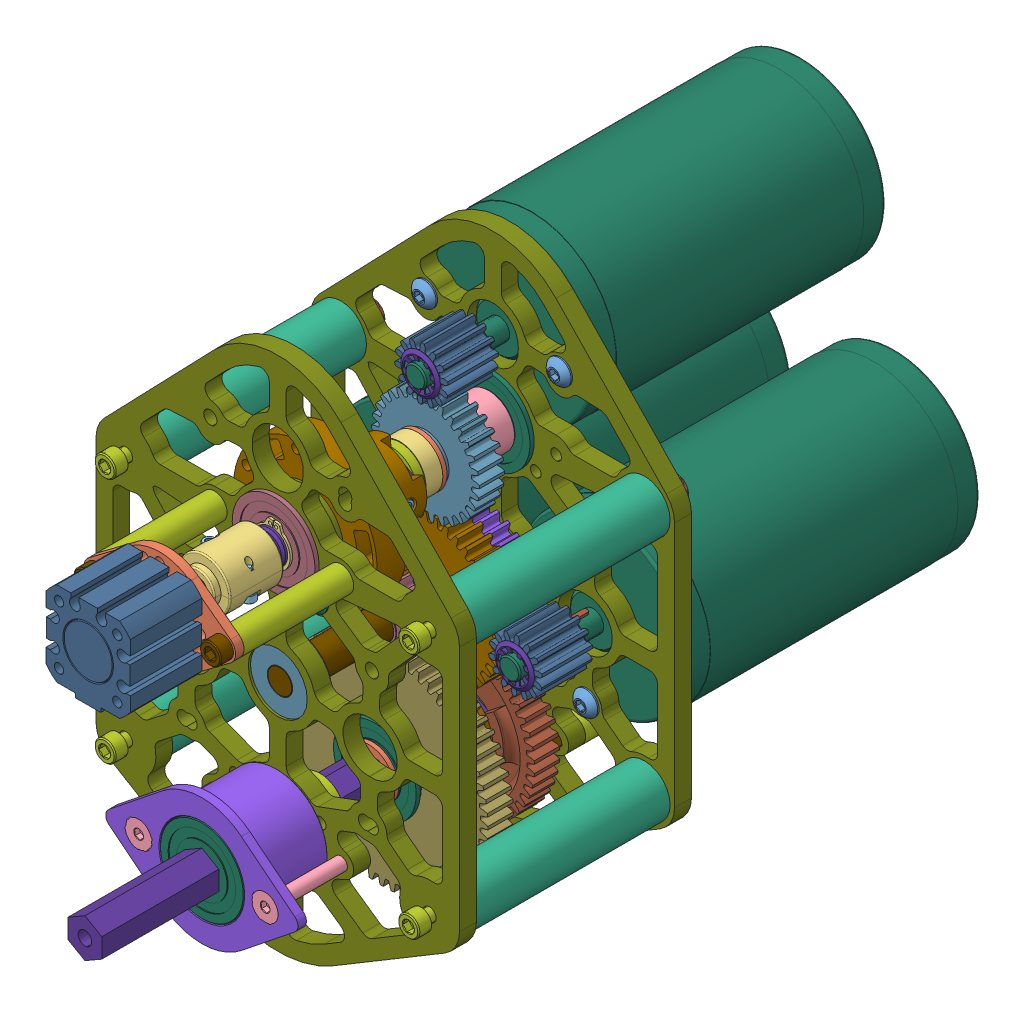
SolidWorks assembly 217-3433-PTO CONFIG STEP, configuration Default. Lengths in mm.
Overall size (140.54 205.19 274.51).
115 component instances, 47 part files, 0 mates.
Components (placement in the parent):
- 217-2428-027 Rev1_97414A630-1: 217-2428-027 Rev1_97414A630 [Default] at (0 -47.0408 -31.6122) x (0 0 1) z (-1 0 0) size (0.64 5.89 7.9)
- 217-3423-005 Rev1-1: 217-3423-005 Rev1 [Default] at (0 -47.0408 -46.0375) size (57.15 38.1 3.17)
- 217-3195-200 Rev1-1: 217-3195-200 Rev1 [Default] at (0 -47.0408 -35.3587) x (-1 0 0) z (0 0 -1) size (20.44 19.56 22.68)
  - 217-3195-010 Rev1-1: 217-3195-010 Rev1 [Default] x (-1 0 0) z (0 0 1) size (19.61 11.78 22.68)
  - 217-3195-010 Rev1-2: 217-3195-010 Rev1 [Default] at origin size (19.61 11.78 22.68)
  - 217-2778-NCQ8A075-050M_1032_Nut_90545A111-1: 217-2778-NCQ8A075-050M_1032_Nut_90545A111 [Default] at (0 0 2.5527) x (-0.5 0.866025 0) z (0 0 1) size (9.53 11 3.39)
  - 91251A107_91251A107-1: 91251A107_91251A107 [Default] at (-7.4168 -4.9375 -0.635) x (1 0 0) z (0 -1 0) size (4.65 4.65 10.79)
  - 91251A107_91251A107-2: 91251A107_91251A107 [Default] at (7.4168 4.9375 -0.635) x (-0.837169 0 -0.546944) z (0 1 0) size (4.65 4.65 10.79)
- 217-3489-1: 217-3489 [Default] at (0 -47.0408 -28.9135) x (0 0 -1) z (0.779786 -0.626046 0) size (4.77 12.7 12.7)
- 217-2428-027 Rev1_97414A630-2: 217-2428-027 Rev1_97414A630 [Default] at (0 45.7708 99.4031) x (0 0 1) z (-0.998671 -0.051538 0) size (0.64 5.89 7.9)
- 217-3195-200 Rev1-2: 217-3195-200 Rev1 [Default] at (0 45.7708 103.048) x (-1 0 0) z (0 0 1) size (20.44 19.56 22.68)
  - 217-3195-010 Rev1-1: 217-3195-010 Rev1 [Default] x (-1 0 0) z (0 0 1) size (19.61 11.78 22.68)
  - 217-3195-010 Rev1-2: 217-3195-010 Rev1 [Default] at origin size (19.61 11.78 22.68)
  - 217-2778-NCQ8A075-050M_1032_Nut_90545A111-1: 217-2778-NCQ8A075-050M_1032_Nut_90545A111 [Default] at (0 0 2.5527) x (-0.5 0.866025 0) z (0 0 1) size (9.53 11 3.39)
  - 91251A107_91251A107-1: 91251A107_91251A107 [Default] at (-7.4168 -4.9375 -0.635) x (1 0 0) z (0 -1 0) size (4.65 4.65 10.79)
  - 91251A107_91251A107-2: 91251A107_91251A107 [Default] at (7.4168 4.9375 -0.635) x (-0.837169 0 -0.546944) z (0 1 0) size (4.65 4.65 10.79)
- 217-3489-2: 217-3489 [Default] at (0 45.7708 96.6028) x (0 0 -1) z (-0.103791 0.994599 0) size (4.77 12.7 12.7)
- 217-3423-005 Rev1-2: 217-3423-005 Rev1 [Default] at (0 45.7708 127) size (57.15 38.1 3.17)
- 217-3423-006 Rev1-1: 217-3423-006 Rev1 [Default] at (-23.8125 -47.0408 -23.8125) x (0 0 1) z (-0.878816 -0.477161 0) size (41.27 9.53 9.53)
- 217-3423-006 Rev1-2: 217-3423-006 Rev1 [Default] at (23.8125 -47.0408 -23.8125) x (0 0 1) z (-1 0 0) size (41.27 9.53 9.53)
- 217-3423-008 Rev1-1: 217-3423-008 Rev1 [Default] at (0 -47.0408 -24.043) x (0 1 0) z (0 0 1) size (7.14 7.14 57.15)
- 217-3423-008 Rev1-2: 217-3423-008 Rev1 [Default] at (0 45.7708 91.7323) x (0 -1 0) z (0 0 -1) size (7.14 7.14 57.15)
- 217-3423-009 Rev1-1: 217-3423-009 Rev1 [Default] at (0 -47.0408 19.5624) x (-1 0 0) z (0 0 1) size (26.99 26.99 13.24)
- 217-3423-009 Rev1-2: 217-3423-009 Rev1 [Default] at (0 45.7708 48.1269) x (-1 0 0) z (0 0 1) size (26.99 26.99 13.24)
- 217-2778-001 Rev2_NCQ8A075-050M-1: 217-2778-001 Rev2_NCQ8A075-050M [Default] at (0 45.7708 142.0495) x (1 0 0) z (0 0 -1) size (31.75 33.34 53.29)
  - 217-2778-NCQ8A075-050M_NCQ8 Tube_075A-1: 217-2778-NCQ8A075-050M_NCQ8 Tube_075A [Default] at origin size (31.75 33.34 26.92)
  - 217-2778-NCQ8A075-050M_NCQ8 Rod_075M-1: 217-2778-NCQ8A075-050M_NCQ8 Rod_075M [Default] at (0 0 4.561) x (-1 0 0) z (0 0 1) size (18.95 18.95 35.27)
  - 217-2778-NCQ8A075-050M_Snap Ring_075-1: 217-2778-NCQ8A075-050M_Snap Ring_075 [Default] at (0 0 10.362) size (21 20.74 0.97)
- 217-2778-001 Rev2_NCQ8A075-050M-2: 217-2778-001 Rev2_NCQ8A075-050M [Default] at (0 -47.0408 -61.087) x (-1 0 0) z (0 0 1) size (31.75 33.34 53.29)
  - 217-2778-NCQ8A075-050M_NCQ8 Tube_075A-1: 217-2778-NCQ8A075-050M_NCQ8 Tube_075A [Default] at origin size (31.75 33.34 26.92)
  - 217-2778-NCQ8A075-050M_NCQ8 Rod_075M-1: 217-2778-NCQ8A075-050M_NCQ8 Rod_075M [Default] at (0 0 4.561) x (-1 0 0) z (0 0 1) size (18.95 18.95 35.27)
  - 217-2778-NCQ8A075-050M_Snap Ring_075-1: 217-2778-NCQ8A075-050M_Snap Ring_075 [Default] at (0 0 10.362) size (21 20.74 0.97)
- 217-2731-1: 217-2731 [Default] at (0 -47.0408 3.175) x (-0.539745 -0.841828 0) z (0.841828 -0.539745 0) size (31.12 7.94 31.12)
- 217-2731-2: 217-2731 [Default] at (0 45.7708 77.7875) x (0.750662 -0.660687 0) z (-0.660687 -0.750662 0) size (31.12 7.94 31.12)
- 217-2733-1: 217-2733 [Default] at (0 0 4.7625) x (0 0 -1) z (0.79471 -0.606989 0) size (7.11 24.61 24.61)
- 217-2733-2: 217-2733 [Default] at (0 0 76.2) x (0 0 1) z (-0.575096 -0.818086 0) size (7.11 24.61 24.61)
- 217-2734-1: 217-2734 [Default] at (0 -47.0408 104.775) x (0 -1 0) z (-1 0 0) size (31.12 7.94 31.12)
- 217-2734-2: 217-2734 [Default] at (0 45.7708 -3.175) x (-0.32713 0.944979 0) z (0.944979 0.32713 0) size (31.12 7.94 31.12)
- 217-2734-3: 217-2734 [Default] at (0 -47.0408 39.6557) x (-0.32713 0.944979 0) z (0.944979 0.32713 0) size (31.12 7.94 31.12)
- 217-2743-1: 217-2743 [Default] at (0 -47.0408 7.9057) x (0 0 -1) z (0.947967 0.31837 0) size (7.94 28.57 28.57)
- 217-2743-2: 217-2743 [Default] at (0 45.7708 73.025) x (0 0 -1) z (0.939414 -0.342784 0) size (7.94 28.57 28.57)
- 217-2614-002_98430A132-1: 217-2614-002_98430A132 [Default] at (35.4115 -3.81 31.1531) x (0 0 -1) z (-0.444133 -0.895961 0) size (1.2 14.83 14.83)
- 217-2614-002_98430A132-2: 217-2614-002_98430A132 [Default] at (35.4115 -3.81 9.9695) x (0 0 1) z (-0.864814 -0.502092 0) size (1.2 14.83 14.83)
- 217-2614-002_98430A132-3: 217-2614-002_98430A132 [Default] at (-35.4115 -3.81 31.1531) x (0 0 -1) z (-0.867628 -0.497214 0) size (1.2 14.83 14.83)
- 217-2614-002_98430A132-4: 217-2614-002_98430A132 [Default] at (-35.4115 -3.81 9.9695) x (0 0 1) z (-0.989494 0.144574 0) size (1.2 14.83 14.83)
- 217-2614-002_98430A132-5: 217-2614-002_98430A132 [Default] at (0 73.7616 31.1531) x (0 0 -1) z (0.241649 -0.970364 0) size (1.2 14.83 14.83)
- 217-2614-002_98430A132-6: 217-2614-002_98430A132 [Default] at (0 73.7616 9.9695) x (0 0 1) z (-0.864814 -0.502092 0) size (1.2 14.83 14.83)
- 217-3421-007 Rev1-1: 217-3421-007 Rev1 [Default] at (23.8125 45.7708 128.5875) x (0 0 -1) z (0.991978 -0.126413 0) size (55.85 7.92 7.92)
- 217-3421-007 Rev1-2: 217-3421-007 Rev1 [Default] at (-23.8125 45.7708 128.5875) x (0 0 -1) z (0.991978 -0.126413 0) size (55.85 7.92 7.92)
- 217-3421-007 Rev1-3: 217-3421-007 Rev1 [Default] at (23.8125 -47.0408 -47.625) x (0 0 1) z (-0.993182 -0.116573 0) size (55.85 7.92 7.92)
- 217-3421-007 Rev1-4: 217-3421-007 Rev1 [Default] at (-23.8125 -47.0408 -47.625) x (0 0 1) z (-0.993182 -0.116573 0) size (55.85 7.92 7.92)
- 217-3421-009 Rev1-1: 217-3421-009 Rev1 [Default] at (-25.4 73.7616 3.175) x (0 0 -1) z (0.999228 -0.039284 0) size (15.78 9.26 9.25)
- 217-3421-009 Rev1-2: 217-3421-009 Rev1 [Default] at (35.4115 21.59 3.175) x (0 0 -1) z (0.999228 -0.039284 0) size (15.78 9.26 9.25)
- 217-3421-009 Rev1-3: 217-3421-009 Rev1 [Default] at (25.4 73.7616 3.175) x (0 0 -1) z (0.656255 -0.754539 0) size (15.78 9.26 9.25)
- 217-3421-009 Rev1-4: 217-3421-009 Rev1 [Default] at (-35.4115 21.59 3.175) x (0 0 -1) z (0.999228 -0.039284 0) size (15.78 9.26 9.25)
- 217-3421-009 Rev1-5: 217-3421-009 Rev1 [Default] at (-35.4115 -29.21 3.175) x (0 0 -1) z (0.999228 -0.039284 0) size (15.78 9.26 9.25)
- 217-3421-009 Rev1-6: 217-3421-009 Rev1 [Default] at (35.4115 -29.21 3.175) x (0 0 -1) z (0.999228 -0.039284 0) size (15.78 9.26 9.25)
- 217-3421-010 Rev1-1: 217-3421-010 Rev1 [Default] at (57.15 45.7708 -3.175) x (0.017497 0.999847 0) z (-0.999847 0.017497 0) size (9.53 6.13 11)
- 217-3421-010 Rev1-2: 217-3421-010 Rev1 [Default] at (57.15 -47.0408 -3.175) x (0.017497 0.999847 0) z (-0.999847 0.017497 0) size (9.53 6.13 11)
- 217-3421-010 Rev1-3: 217-3421-010 Rev1 [Default] at (-57.15 45.7708 -3.175) x (0.017497 0.999847 0) z (-0.999847 0.017497 0) size (9.53 6.13 11)
- 217-3421-010 Rev1-4: 217-3421-010 Rev1 [Default] at (-57.15 -47.0408 -3.175) x (0.017497 0.999847 0) z (-0.999847 0.017497 0) size (9.53 6.13 11)
- 217-3421-011 Rev2_97633A200-1: 217-3421-011 Rev2_97633A200 [Default] at (0 45.7708 86.1695) x (0 0 1) z (-0.99554 0.094343 0) size (0.89 16.1 14.34)
- 217-3421-011 Rev2_97633A200-2: 217-3421-011 Rev2_97633A200 [Default] at (0 -47.0408 -5.2388) x (0 0 1) z (-0.999986 0.005305 0) size (0.89 16.1 14.34)
- 217-3422-007 Rev1-1: 217-3422-007 Rev1 [Default] at (23.8125 -47.0408 109.4868) x (0 0 1) z (-0.947089 0.320972 0) size (35.11 10.21 10.21)
- 217-3422-007 Rev1-2: 217-3422-007 Rev1 [Default] at (-23.8125 -47.0408 109.4868) x (0 0 1) z (-0.947089 0.320972 0) size (35.11 10.21 10.21)
- 217-3423-014 Rev1-1: 217-3423-014 Rev1 [Default] at (-13.4938 -47.0408 19.5624) x (0 0.998248 0.059168) z (-1 0 0) size (4.65 4.65 26.79)
- 217-3423-014 Rev1-2: 217-3423-014 Rev1 [Default] at (-13.4938 45.7708 48.1269) x (0 -0.673339 -0.739334) z (-1 0 0) size (4.65 4.65 26.79)
- 217-3423-016 Rev1-1: 217-3423-016 Rev1 [Default] at (16.1541 -37.7142 -4.7625) x (0 0 1) z (-0.958364 -0.285548 0) size (11.03 9.26 9.25)
- 217-3423-016 Rev1-2: 217-3423-016 Rev1 [Default] at (-16.1541 -37.7142 -4.7625) x (0 0 1) z (-0.958364 -0.285548 0) size (11.03 9.26 9.25)
- 217-3423-016 Rev1-3: 217-3423-016 Rev1 [Default] at (0 -65.6939 -4.7625) x (0 0 1) z (0.993879 0.110476 0) size (11.03 9.26 9.25)
- 217-3424-003 Rev1-1: 217-3424-003 Rev1 [Default] at (57.15 -47.0408 87.3125) x (0 0 -1) z (0.754419 0.656393 0) size (100.3 7.92 7.92)
- 217-3424-003 Rev1-2: 217-3424-003 Rev1 [Default] at (-57.15 -47.0408 87.3125) x (0 0 -1) z (0.754419 0.656393 0) size (100.3 7.92 7.92)
- 217-3424-003 Rev1-3: 217-3424-003 Rev1 [Default] at (-57.15 45.7708 87.3125) x (0 0 -1) z (0.754419 0.656393 0) size (100.3 7.92 7.92)
- 217-3424-003 Rev1-4: 217-3424-003 Rev1 [Default] at (57.15 45.7708 87.3125) x (0 0 -1) z (0.754419 0.656393 0) size (100.3 7.92 7.92)
- 217-3210-001 Rev1_30t-1: 217-3210-001 Rev1_30t [Default] at (0 0 11.0871) x (0.892842 -0.450371 0) z (0 0 1) size (41.01 41.12 12.65)
- 217-3215-001 Rev1_42t-1: 217-3215-001 Rev1_42t [Default] at (0 0 23.7363) x (-0.743738 0.668471 0) z (0 0 1) size (56.22 56.3 12.65)
- 217-3414-001 Rev1_14t Steel Pinion-1: 217-3414-001 Rev1_14t Steel Pinion [Default] at (-35.4115 -3.81 20.5613) x (0.095909 -0.99539 0) z (0 0 1) size (20.32 20.6 19.05)
- 217-3414-001 Rev1_14t Steel Pinion-2: 217-3414-001 Rev1_14t Steel Pinion [Default] at (35.4115 -3.81 20.5613) x (-0.277698 -0.960668 0) z (0 0 1) size (20.32 20.6 19.05)
- 217-3414-001 Rev1_14t Steel Pinion-3: 217-3414-001 Rev1_14t Steel Pinion [Default] at (0 73.7616 20.5613) x (-0.277698 -0.960668 0) z (0 0 1) size (20.32 20.6 19.05)
- 217-3418-001 Rev2_44t-1: 217-3418-001 Rev2_44t [Default] at (0 -47.0408 11.922) x (0.76226 0.647271 0) z (0 0 1) size (58.67 58.67 9.53)
- 217-3420-001 Rev2_60t-1: 217-3420-001 Rev2_60t [Default] at (0 -47.0408 39.6082) x (-0.373856 -0.927487 0) z (0 0 -1) size (78.95 78.95 9.53)
- 217-3100-001_14t-1: 217-3100-001_14t [Default] at (0 0 39.6875) x (0.998696 0.051045 0) z (0 0 1) size (20.32 20.6 12.7)
- 217-2705-001_30t-1: 217-2705-001_30t [Default] at (0 45.7708 23.7871) x (0.993036 0.117815 0) z (0 0 1) size (41.01 41.12 12.65)
- 217-2000-1: 217-2000 [Default] at (35.4115 -3.81 -3.175) x (0 0 -1) z (1 0 0) size (150.2 64.01 64.01)
- 217-2000-2: 217-2000 [Default] at (-35.4115 -3.81 -3.175) x (0 0 -1) z (1 0 0) size (150.2 64.01 64.01)
- 217-2000-3: 217-2000 [Default] at (0 73.7616 -3.175) x (0 0 -1) z (0 1 0) size (150.2 64.01 64.01)
- 217-3433-001 Rev1_Default_As Machined_-1: 217-3433-001 Rev1_Default_As Machined_ [Default] at origin size (136.86 194.46 6.35)
- 217-3433-001 Rev1_Default_As Machined_-2: 217-3433-001 Rev1_Default_As Machined_ [Default] at (0 0 80.9625) x (-1 0 0) z (0 0 -1) size (136.86 194.46 6.35)
- 217-3423-003 Rev1-1: 217-3423-003 Rev1 [Default] at (0 -47.0408 25.7651) x (0 -1 0) z (0 0 1) size (18.33 15.88 164.14)
- 217-3423-003 Rev1-2: 217-3423-003 Rev1 [Default] at (0 45.7708 55.1656) x (0 1 0) z (0 0 -1) size (18.33 15.88 164.14)
- 217-3424-005 Rev1-1: 217-3424-005 Rev1 [Default] at (0 0 40.4813) x (0 -1 0) z (0 0 1) size (11.11 11.11 85.72)
- 217-3256-001 Rev1-1: 217-3256-001 Rev1 [Default] at (0 0 31.6484) size (15.88 15.88 3.17)
- 217-3257-001 Rev1-1: 217-3257-001 Rev1 [Default] at (0 45.7708 30.9563) size (19.5 19.5 1.59)
- 217-3257-001 Rev1-2: 217-3257-001 Rev1 [Default] at (0 -47.0408 49.1298) size (19.5 19.5 1.59)
- 217-3259-001 Rev1-1: 217-3259-001 Rev1 [Default] at (0 45.7708 34.925) x (0.995688 -0.092763 0) z (0 0 1) size (19.5 19.5 6.35)
- 217-3261-001 Rev1-1: 217-3261-001 Rev1 [Default] at (0 45.7708 11.1125) size (19.5 19.5 12.7)
- 217-3423-004 Rev1-1: 217-3423-004 Rev1 [Default] at (0 -47.0408 3.556) size (19.05 19.05 0.76)
- 217-3423-006 Rev1-3: 217-3423-006 Rev1 [Default] at (-23.8125 45.7708 104.775) x (0 0 1) z (-1 0 0) size (41.27 9.53 9.53)
- 217-3423-006 Rev1-4: 217-3423-006 Rev1 [Default] at (23.8125 45.7708 104.775) x (0 0 1) z (-1 0 0) size (41.27 9.53 9.53)
- 217-3424-002 Rev1-1: 217-3424-002 Rev1 [Default] at (-57.15 -47.0408 40.4813) size (19.13 19.13 80.96)
- 217-3424-002 Rev1-2: 217-3424-002 Rev1 [Default] at (57.15 -47.0408 40.4813) x (0.857249 -0.514902 0) z (0 0 1) size (19.13 19.13 80.96)
- 217-3424-002 Rev1-3: 217-3424-002 Rev1 [Default] at (-57.15 45.7708 40.4813) x (0.857249 -0.514902 0) z (0 0 1) size (19.13 19.13 80.96)
- 217-3424-002 Rev1-4: 217-3424-002 Rev1 [Default] at (57.15 45.7708 40.4813) x (0.982113 0.18829 0) z (0 0 1) size (19.13 19.13 80.96)
- 217-2758-001 Rev1-1: 217-2758-001 Rev1 [Default] at (0 45.7708 39.6875) x (0.999998 -0.001993 0) z (0 0 1) size (19.05 19.05 3.17)
- 217-3422-004 Rev2-1: 217-3422-004 Rev2 [Default] at (0 -47.0408 111.125) size (72.39 47.62 34.67)
- 217-3433-002 Rev1-1: 217-3433-002 Rev1 [Default] at (0 45.7708 69.0087) x (0.144045 -0.989571 0) z (0 0 -1) size (53.98 53.98 14.29)
- 217-3263-001 Rev1-1: 217-3263-001 Rev1 [Default] at (0 -47.0408 92.075) x (0.964295 0.26483 0) z (0 0 1) size (19.5 19.5 25.4)
- 217-2758-001 Rev1-2: 217-2758-001 Rev1 [Default] at (0 -47.0408 69.85) x (0.99994 -0.010919 0) z (0 0 1) size (19.05 19.05 3.17)
- 217-2761-001 rev1-1: 217-2761-001 rev1 [Default] at (35.4115 -0.01 12.925) size (2 2 20)
- 217-2761-001 rev1-2: 217-2761-001 rev1 [Default] at (-35.4115 -0.01 12.925) size (2 2 20)
- 217-2761-001 rev1-3: 217-2761-001 rev1 [Default] at (-3.8 73.7616 12.925) x (0 1 0) z (0 0 1) size (2 2 20)
- 217-3423-004 Rev1-2: 217-3423-004 Rev1 [Default] at (0 45.7708 77.3748) size (19.05 19.05 0.76)
- 217-3423-016 Rev1-4: 217-3423-016 Rev1 [Default] at (-16.1541 36.4442 85.725) x (0 0 -1) z (1 0 0) size (11.03 9.26 9.25)
- 217-3423-016 Rev1-5: 217-3423-016 Rev1 [Default] at (16.1541 36.4442 85.725) x (0 0 -1) z (1 0 0) size (11.03 9.26 9.25)
- 217-3257-001 Rev1-3: 217-3257-001 Rev1 [Default] at (0 -47.0408 72.2313) size (19.5 19.5 1.59)
